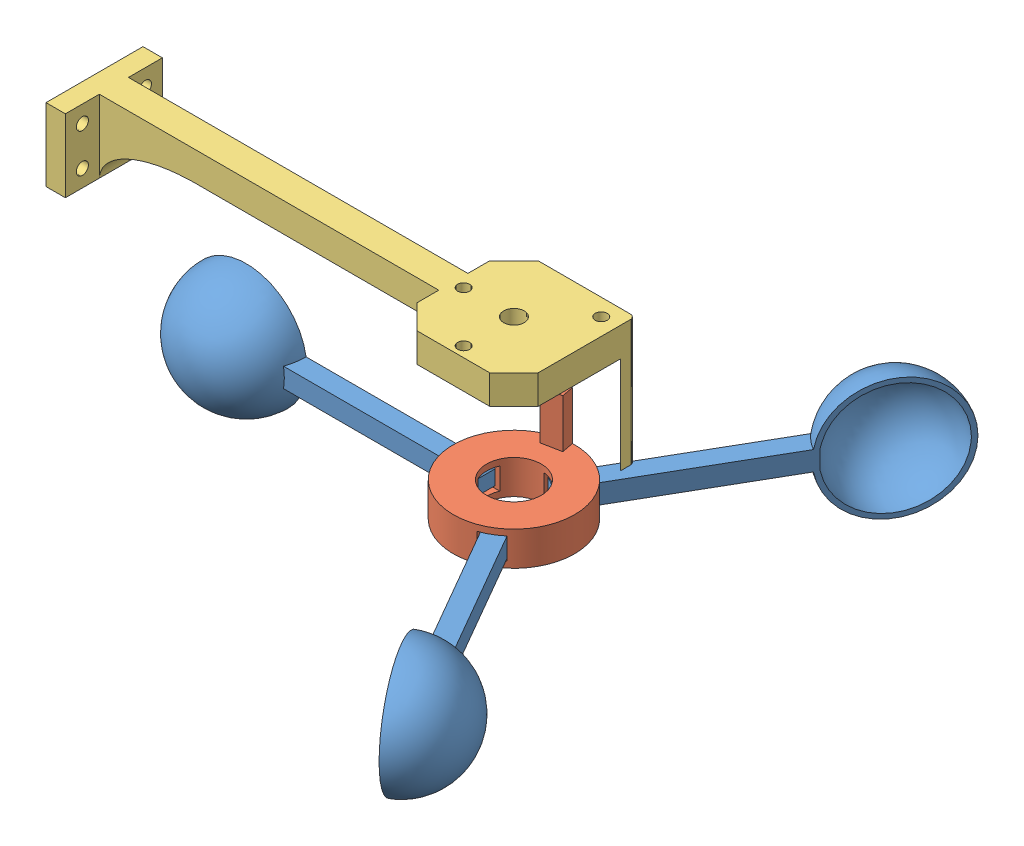
SolidWorks assembly anomometre, configuration Défaut. Lengths in mm.
Overall size (261.07 89.68 252.58).
5 component instances, 3 part files, 10 mates.
Components (placement in the parent):
- coque-1: coque [Défaut] at origin size (127.65 50 25)
- soutient-1: soutient [Défaut] at (113.8995 -7.5 3.5) x (0.5 0 -0.866025) z (0 1 0) size (50 50 34)
- coque-2: coque [Défaut] at (167.8182 0 103.8899) x (-0.5 0 -0.866025) z (0.866025 0 -0.5) size (127.65 50 25)
- coque-3: coque [Défaut] at (174.7464 0 -92.8899) x (-0.5 0 0.866025) z (-0.866025 0 -0.5) size (127.65 50 25)
- pied-1: pied [Défaut] at (44.4877 64.6821 9.5426) x (1 0 0) z (0 0 -1) size (198 52 50)
Mates (geometry in assembly coordinates):
- Coïncidente8: coincident anti-aligned: plane of coque-1 through (22.6495 4 8) normal (0 1 0); plane of soutient-1 through (103.8995 4 8) normal (0 -1 0)
- Coïncidente14: coincident anti-aligned: plane of soutient-1 through (122.7966 4 9.9103) normal (-0.866025 0 0.5); plane of coque-2 through (174.7464 0 99.8899) normal (0.866025 0 -0.5)
- Coïncidente16: coincident anti-aligned: plane of soutient-1 through (122.7966 4 9.9103) normal (0 -1 0); plane of coque-2 through (163.4216 4 80.2748) normal (0 1 0)
- Coïncidente21: coincident anti-aligned: plane of soutient-1 through (122.7966 4 -2.9103) normal (-0.866025 0 -0.5); plane of coque-3 through (174.7464 0 -92.8899) normal (0.866025 0 0.5)
- Coïncidente23: coincident anti-aligned: plane of soutient-1 through (115.0024 4 -7.4103) normal (0 -1 0); plane of coque-3 through (156.4934 4 -77.2748) normal (0 1 0)
- Coaxiale2: concentric aligned: cylinder of soutient-1 through (113.8995 8.5 3.5) axis (0 -1 0) radius 11.25; cylinder of pied-1 through (113.8995 64.6822 3.5) axis (0 -1 0) radius 4.25
- Coïncidente28: coincident anti-aligned: plane of coque-1 through (0 0 8) normal (0 0 1); plane of soutient-1 through (103.8995 4 8) normal (0 0 -1)
- Tangent2: tangent anti-aligned: cylinder of soutient-1 through (113.8995 8.5 3.5) axis (0 -1 0) radius 11.25; plane of coque-3 through (116.4934 4 -7.9928) normal (-0.5 0 0.866025)
- Tangent3: tangent anti-aligned: plane of coque-1 through (102.6495 4 8) normal (1 0 0); cylinder of soutient-1 through (113.8995 8.5 3.5) axis (0 -1 0) radius 11.25
- Tangent4: tangent anti-aligned: cylinder of soutient-1 through (113.8995 8.5 3.5) axis (0 -1 0) radius 11.25; plane of coque-2 through (123.4216 4 10.9928) normal (-0.5 0 -0.866025)
